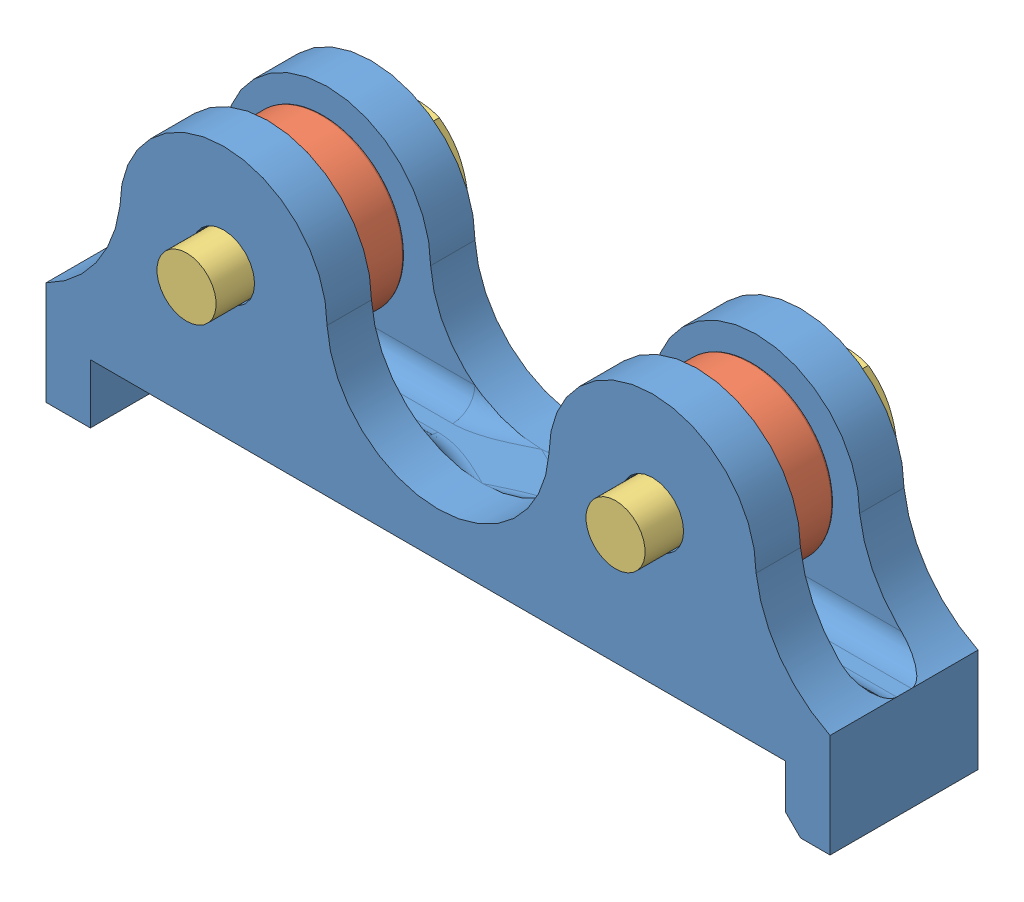
SolidWorks assembly extruder_spool_holder, configuration Défaut. Lengths in mm.
Overall size (106.92 42.17 31).
5 component instances, 3 part files, 6 mates.
Components (placement in the parent):
- spool_roller-1: spool_roller [Défaut] at origin size (106.92 42 20)
- instrument ball bearing_68_am-1: instrument ball bearing_68_am [AFBMA 12.1.4.1 - 0080-22 - 8,SI,NC,8_68] at (-29 14 10) x (0 0 1) z (-0.935629 -0.352984 0) size (7 22 22)
- hex screw_am-1: hex screw_am [B18.6.7M - M8 x 1.25 x 25 Indented HHMS --25N] at (-29 14 -6) x (0 0 1) z (-0.866025 -0.5 0) size (31 15.01 13)
- instrument ball bearing_68_am-7: instrument ball bearing_68_am [AFBMA 12.1.4.1 - 0080-22 - 8,SI,NC,8_68] at (29 14 10) x (0 0 1) z (-0.935629 0.352984 0) size (7 22 22)
- hex screw_am-2: hex screw_am [B18.6.7M - M8 x 1.25 x 25 Indented HHMS --25N] at (29 14 -6) x (0 0 1) z (-0.866025 0.5 0) size (31 15.01 13)
Mates (geometry in assembly coordinates):
- Coïncidente2: coincident anti-aligned: plane of spool_roller-1 through (0 0 0) normal (0 0 -1); plane of hex screw_am-1 through (-31 17.4641 0) normal (0 0 1)
- Coaxiale4: concentric aligned: cylinder of spool_roller-1 through (-29 14 10.001) axis (0 0 -1) radius 4.2; cylinder of hex screw_am-1 through (-29 14 -31.4) axis (0 0 -1) radius 4
- Coaxiale5: concentric anti-aligned: cylinder of instrument ball bearing_68_am-1 through (-29 14 -10.6375) axis (0 0 1) radius 4; cylinder of hex screw_am-1 through (-29 14 -31.4) axis (0 0 -1) radius 4
- Coïncidente3: coincident anti-aligned: plane of spool_roller-1 through (-29 14 6.5) normal (0 0 1); plane of instrument ball bearing_68_am-1 through (-31.1532 19.7073 6.5) normal (0 0 -1)
- Coïncidente4: coordinate: point of spool_roller-1; point of assembly
- Parallèle1: parallel anti-aligned: plane of spool_roller-1 through (-47 -6 10) normal (0 -1 0); plane of hex screw_am-1 through (-32.7528 20.5 0) normal (0 1 0)
